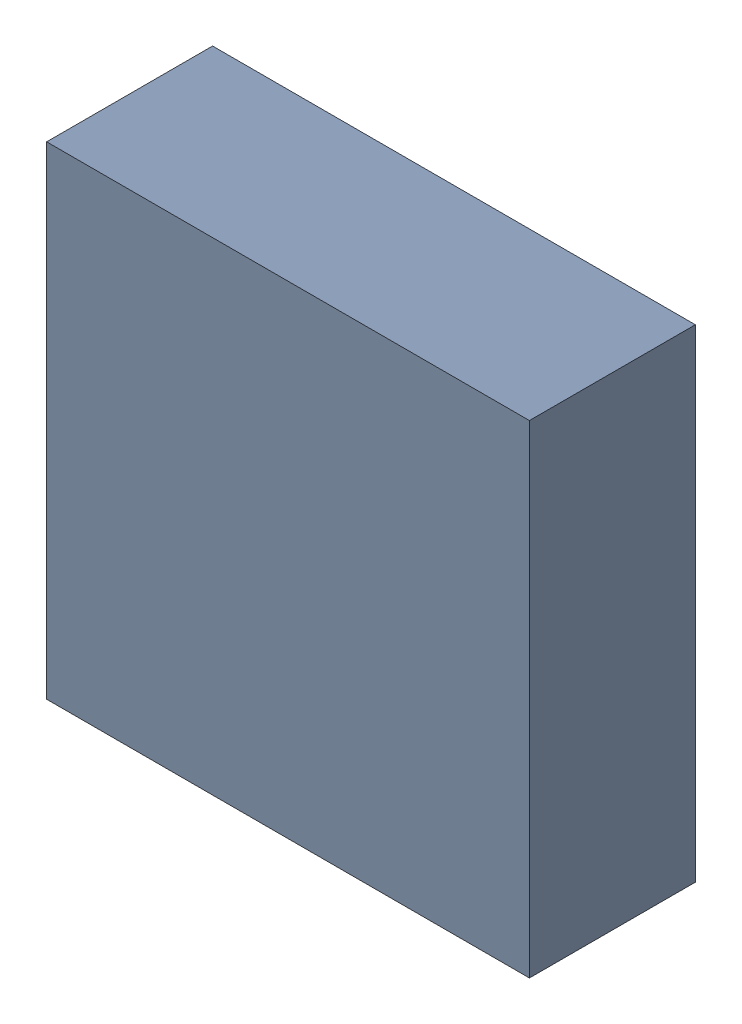
SolidWorks assembly U305_1PCB, configuration Default. Lengths in mm.
Overall size (3.2 3.2 1.1).
2 component instances, 1 part files, 0 mates.
Components (placement in the parent):
- 846484240-1: 846484240 [Default] at (129.9 111.2 -2.7638) size (3.2 3.2 1.1)
  - Extruded_11-1: Extruded_11 [Default] at origin size (3.2 3.2 1.1)
